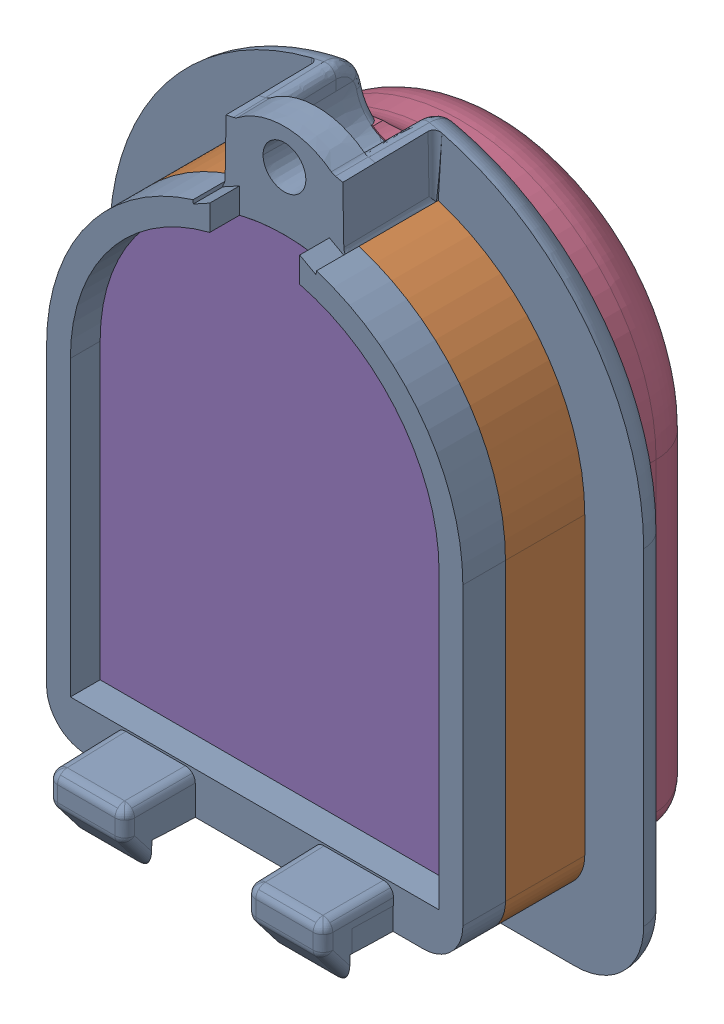
SolidWorks assembly Digit813_0.6Out, configuration 默认. Lengths in mm.
Overall size (26.95 34.26 16.46).
5 component instances, 5 part files, 13 mates.
Components (placement in the parent):
- OriginBody-1: OriginBody [默认] at (-2.213 7.3799 -8.324) size (26.95 34.26 11.2)
- TransBody-1: TransBody [默认] at (-2.213 7.3799 -8.324) size (21 26.93 4)
- InsideSKin-2: InsideSKin [默认] at (-2.213 4.0799 -7.824) x (-1 0 0) z (0 0 -1) size (18.6 25.2 5.2)
- outSkin-1: outSkin [默认] at (-2.213 4.0799 -7.824) x (-1 0 0) z (0 0 -1) size (21.4 28.04 5.8)
- Lens-1: Lens [默认] at (-2.213 7.3799 -7.824) size (18.6 25.2 5.65)
Mates (geometry in assembly coordinates):
- 重合1: coincident anti-aligned: plane of OriginBody-1 through (-2.213 7.3799 -6.824) normal (0 0 1); plane of TransBody-1 through (7.137 -9.7124 -6.824) normal (0 0 -1)
- 同心1: concentric aligned: cylinder of OriginBody-1 through (-2.213 7.3799 -0.674) axis (0 0 -1) radius 10.5; cylinder of TransBody-1 through (-2.213 7.3799 -0.674) axis (0 0 -1) radius 10.5
- 重合2: coincident aligned: plane of OriginBody-1 through (8.287 7.3799 -0.674) normal (1 0 0); plane of TransBody-1 through (8.287 7.3799 -0.674) normal (1 0 0)
- 重合3: coincident anti-aligned: plane of TransBody-1 through (-2.213 -8.5201 48.523) normal (0 1 0); plane of Lens-1 through (-11.513 -8.5201 -2.174) normal (0 -1 0)
- 同心2: concentric aligned: cylinder of TransBody-1 through (-2.213 7.3799 48.523) axis (0 0 -1) radius 9.3; cylinder of Lens-1 through (-2.213 7.3799 -2.174) axis (0 0 -1) radius 9.3
- 平行2: parallel aligned: plane of InsideSKin-2 through (-11.013 -8.5201 -13.024) normal (0 -1 0); plane of outSkin-1 through (-11.013 -9.1201 -13.024) normal (0 -1 0)
- 距离1: distance = 0.5 mm anti-aligned: plane of OriginBody-1 through (-2.2735 3.9424 -8.324) normal (0 0 -1); plane of outSkin-1 through (-11.013 -8.0201 -7.824) normal (0 0 1)
- 同心5: concentric aligned: cone of OriginBody-1 through (-2.213 19.6299 -3.824) axis (0 0 1); cylinder of outSkin-1 through (-2.213 19.6299 -17.824) axis (0 0 1) radius 2.0018
- 同心6: concentric aligned: cone of OriginBody-1 through (-2.213 19.6299 -3.824) axis (0 0 1); cylinder of outSkin-1 through (-2.213 19.6299 -17.824) axis (0 0 1) radius 2.0018
- 重合10: coincident anti-aligned: plane of InsideSKin-2 through (-11.013 -8.0201 -7.824) normal (0 0 1); plane of Lens-1 through (-2.213 7.3799 -7.824) normal (0 0 -1)
- 同心8: concentric anti-aligned: circle of InsideSKin-2; circle of Lens-1
- 同心9: concentric aligned: cone of OriginBody-1 through (-2.213 19.6299 -3.824) axis (0 0 1); cylinder of outSkin-1 through (-2.213 19.6299 -17.824) axis (0 0 1) radius 2.0018
- 重合11: coincident aligned: plane of OriginBody-1 through (-2.213 7.3799 -2.174) normal (0 0 1); plane of Lens-1 through (-2.213 7.3799 -2.174) normal (0 0 1)
